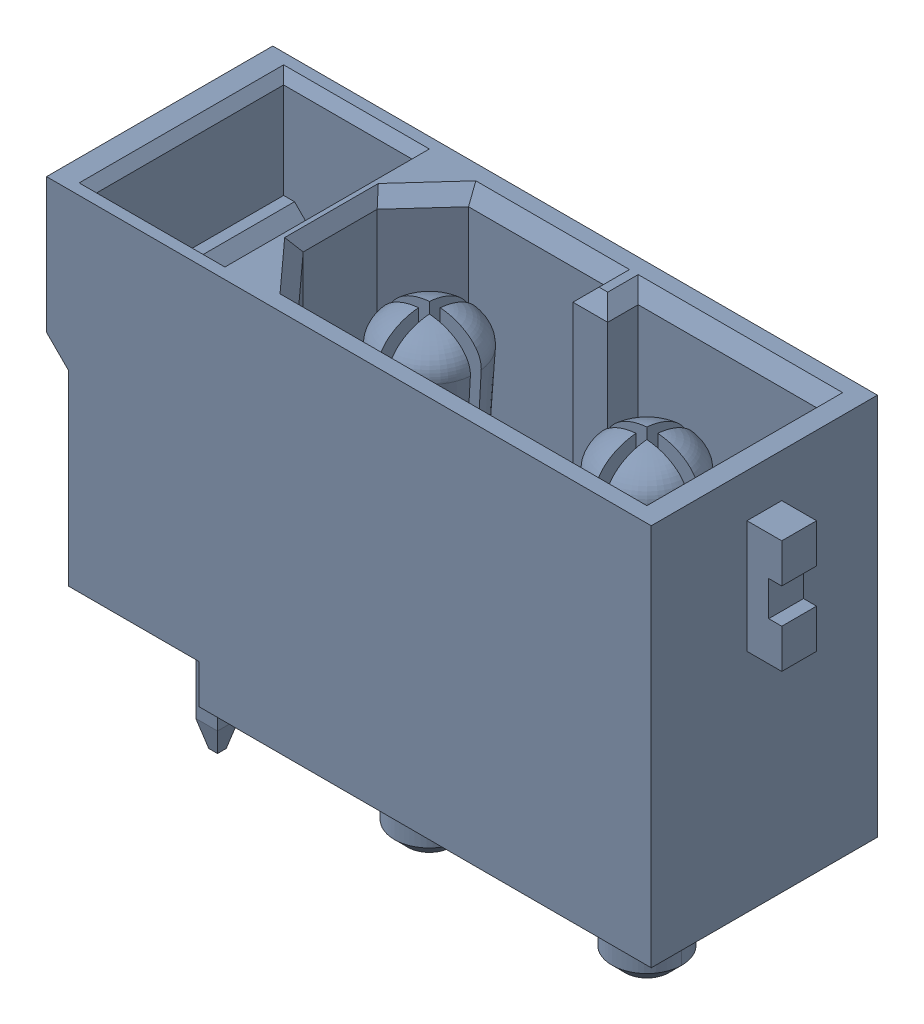
SolidWorks assembly 0518_ASM_2_ASM_1_ASM_1_ASM_1_AS_ASM.stp, configuration 默认. Lengths in mm.
Overall size (15.5 11.3 5.2).
2 component instances, 1 part files, 0 mates.
Components (placement in the parent):
- 12345_ASM_1_ASM_2_ASM_1_ASM_1_A_ASM.stp-1: 12345_ASM_1_ASM_2_ASM_1_ASM_1_A_ASM.stp [默认] at origin size (15.5 11.3 5.2)
  - DUANZI_1_3_1_1_1_1_1_1.stp-1: DUANZI_1_3_1_1_1_1_1_1.stp [默认] at (-0.1798 16.5474 0.4329) x (0 0 -1) z (0 1 0) size (5.2 15.5 11.3)
